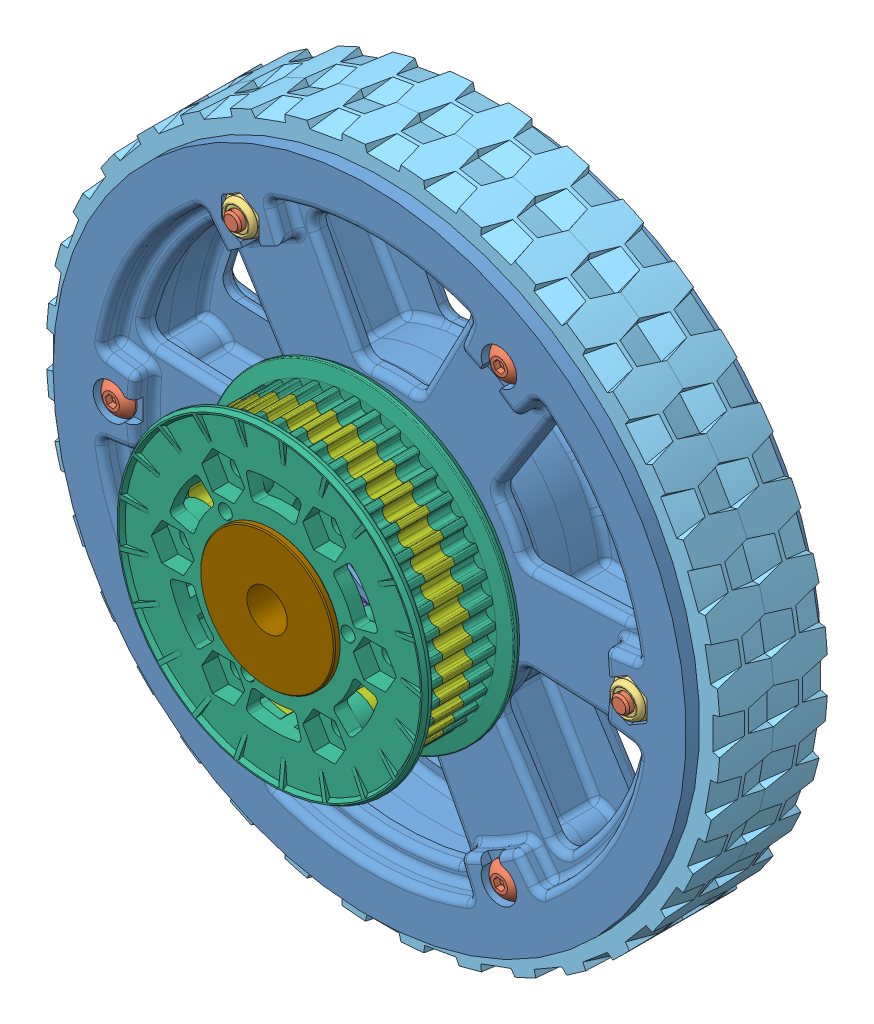
SolidWorks assembly Wheel Drive Free  2.2, configuration 6in Wheel. Lengths in mm.
Overall size (158.75 158.75 58.13).
57 component instances, 11 part files, 21 mates.
Components (placement in the parent):
- 217-2589 1in.20121203-1: 217-2589 1in.20121203 [Default] at origin size (158.75 158.75 36.2)
  - 217-2589-001 Rev3-1: 217-2589-001 Rev3 [Default] at origin size (149.22 149.22 19.81)
  - 217-2589-001 Rev3-2: 217-2589-001 Rev3 [Default] x (-1 0 0) z (0 0 -1) size (149.22 149.22 19.81)
  - SCREW-832-1250-1: SCREW-832-1250 [Default] at (60.96 0 -15.8623) x (0 0 1) z (-1 0 0) size (33.96 7.92 7.92)
  - NUT-832-NYLOCK-1: NUT-832-NYLOCK [Default] at (60.96 0 12.0688) x (0.866025 0.5 0) z (0.5 -0.866025 0) size (10.2 5.86 8.12)
  - BEAM-0750-1: BEAM-0750 [Default] at (11.9062 -20.6222 0.0635) x (0.866025 0.5 0) z (-0.5 0.866025 0) size (7.34 19.93 7.34)
  - BEAM-0750-2: BEAM-0750 [Default] at (-11.9062 -20.6222 0.0635) x (0.866025 -0.5 0) z (0.5 0.866025 0) size (7.34 19.93 7.34)
  - BEAM-0750-3: BEAM-0750 [Default] at (-23.8125 0 0.0635) x (0 -1 0) z (1 0 0) size (7.34 19.93 7.34)
  - BEAM-0750-4: BEAM-0750 [Default] at (-11.9062 20.6222 0.0635) x (-0.866025 -0.5 0) z (0.5 -0.866025 0) size (7.34 19.93 7.34)
  - BEAM-0750-5: BEAM-0750 [Default] at (11.9062 20.6222 0.0635) x (-0.866025 0.5 0) z (-0.5 -0.866025 0) size (7.34 19.93 7.34)
  - BEAM-0750-6: BEAM-0750 [Default] at (23.8125 0 0.0635) x (0 1 0) z (-1 0 0) size (7.34 19.93 7.34)
  - SCREW-832-1250-2: SCREW-832-1250 [Default] at (30.48 52.7929 15.8623) x (0 0 -1) z (0.923728 0.383049 0) size (33.96 7.92 7.92)
  - NUT-832-NYLOCK-2: NUT-832-NYLOCK [Default] at (30.48 52.7929 -12.0688) x (-0.866025 -0.5 0) z (0.5 -0.866025 0) size (10.2 5.86 8.12)
  - NUT-832-NYLOCK-3: NUT-832-NYLOCK [Default] at (30.48 -52.7929 -12.0688) x (0 1 0) z (-1 0 0) size (10.2 5.86 8.12)
  - NUT-832-NYLOCK-4: NUT-832-NYLOCK [Default] at (-60.96 0 -12.0688) x (0.866025 -0.5 0) z (0.5 0.866025 0) size (10.2 5.86 8.12)
  - SCREW-832-1250-3: SCREW-832-1250 [Default] at (-30.48 -52.7929 -15.8623) x (0 0 1) z (0.5 0.866025 0) size (33.96 7.92 7.92)
  - SCREW-832-1250-4: SCREW-832-1250 [Default] at (-30.48 52.7929 -15.8623) x (0 0 1) z (0.5 -0.866025 0) size (33.96 7.92 7.92)
  - NUT-832-NYLOCK-5: NUT-832-NYLOCK [Default] at (-30.48 -52.7929 12.0688) x (0 -1 0) z (-1 0 0) size (10.2 5.86 8.12)
  - NUT-832-NYLOCK-6: NUT-832-NYLOCK [Default] at (-30.48 52.7929 12.0688) x (-0.866025 0.5 0) z (0.5 0.866025 0) size (10.2 5.86 8.12)
  - SCREW-832-1250-5: SCREW-832-1250 [Default] at (30.48 -52.7929 15.8623) x (0 0 -1) z (-0.130134 -0.991496 0) size (33.96 7.92 7.92)
  - SCREW-832-1250-6: SCREW-832-1250 [Default] at (-60.96 0 15.8623) x (0 0 -1) z (-0.793594 0.608447 0) size (33.96 7.92 7.92)
  - 217-2860-001 Rev3-1: 217-2860-001 Rev3 [Default] at (0 0 -6.35) size (158.75 158.75 12.71)
  - 217-2860-001 Rev3-2: 217-2860-001 Rev3 [Default] at (0 0 6.35) size (158.75 158.75 12.71)
- 217-3199-STEP-1: 217-3199-STEP [Default] at (0 0 36.875) x (0 -1 0) z (0 0 1) size (73 73 23.01)
  - 217-3199-001 Rev4-1: 217-3199-001 Rev4 [Default] at origin size (73 73 11.51)
  - 217-3199-001 Rev4-2: 217-3199-001 Rev4 [Default] at (0 0 -17.825) x (-1 0 0) z (0 0 -1) size (73 73 11.51)
  - 217-3199-002 Rev3-1: 217-3199-002 Rev3 [Default] at (0 0 -5.5) x (-1 0 0) z (0 0 1) size (65.74 65.61 14)
- 217-3234-STEP-1: 217-3234-STEP [Default] at (0 0 14.2875) x (0.866025 -0.5 0) z (0.5 0.866025 0)
- 3_8 id 1-1_8 od Flanged Ball Bearing (am-0573)-1: 3_8 id 1-1_8 od Flanged Ball Bearing (am-0573) [Default] at (0 0 36.0749) x (0 0 1) z (-1 0 0)
- 3_8 id 1-1_8 od Flanged Ball Bearing (am-0573)-3: 3_8 id 1-1_8 od Flanged Ball Bearing (am-0573) [Default] at (0 0 -36.0749) x (0 0 -1) z (1 0 0) (suppressed, hidden)
- 217-3234-STEP-2: 217-3234-STEP [Default] at (0 0 -14.2875) x (0.866025 -0.5 0) z (0.5 0.866025 0) (suppressed, hidden)
- 217-3199-STEP-2: 217-3199-STEP [Default] at (0 0 -19.05) x (0 -1 0) z (0 0 1) size (73 73 23.01) (suppressed, hidden)
  - 217-3199-001 Rev4-1: 217-3199-001 Rev4 [Default] at origin size (73 73 11.51)
  - 217-3199-001 Rev4-2: 217-3199-001 Rev4 [Default] at (0 0 -17.825) x (-1 0 0) z (0 0 -1) size (73 73 11.51)
  - 217-3199-002 Rev3-1: 217-3199-002 Rev3 [Default] at (0 0 -5.5) x (-1 0 0) z (0 0 1) size (65.74 65.61 14)
- 3_8 id 1-1_8 od Flanged Ball Bearing (am-0573)-4: 3_8 id 1-1_8 od Flanged Ball Bearing (am-0573) [Default] at (0 0 -8.7249) x (0 0 -1) z (0.923728 0.383049 0)
- 217-2605 1in.20121203-1: 217-2605 1in.20121203 [Default] at origin size (273.24 273.24 34.92) (suppressed, hidden)
  - SBS1_SBS0832-1250SS-1: SBS1_SBS0832-1250SS [Default] at (-86.36 0 -16.4973) x (0 0 1) z (0.950435 -0.310923 0) size (34.41 8.02 7.99)
  - SBS1_SBS0832-1250SS-2: SBS1_SBS0832-1250SS [Default] at (-43.18 74.79 16.4973) x (0 0 -1) z (-0.955409 -0.295284 0) size (34.41 8.02 7.99)
  - NUT-832-NYLOCK-1: NUT-832-NYLOCK [Default] at (-86.36 0 12.0688) x (0.866025 0.5 0) z (0.5 -0.866025 0) size (10.2 5.86 8.12)
  - NUT-832-NYLOCK-2: NUT-832-NYLOCK [Default] at (-43.18 74.79 -12.0688) x (-0.866025 -0.5 0) z (0.5 -0.866025 0) size (10.2 5.86 8.12)
  - 217-2605-001 Rev1-1: 217-2605-001 Rev1 [Default] x (-0.5 0.866025 0) z (0 0 1) size (200.03 200.03 19.71)
  - 217-2605-001 Rev1-2: 217-2605-001 Rev1 [Default] x (-1 0 0) z (0 0 -1) size (200.03 200.03 19.71)
  - NUT-832-NYLOCK-3: NUT-832-NYLOCK [Default] at (86.36 0 -12.0688) x (0 1 0) z (-1 0 0) size (10.2 5.86 8.12)
  - NUT-832-NYLOCK-4: NUT-832-NYLOCK [Default] at (-43.18 -74.79 -12.0688) x (0.866025 -0.5 0) z (0.5 0.866025 0) size (10.2 5.86 8.12)
  - NUT-832-NYLOCK-5: NUT-832-NYLOCK [Default] at (43.18 74.79 12.0688) x (0 -1 0) z (-1 0 0) size (10.2 5.86 8.12)
  - NUT-832-NYLOCK-6: NUT-832-NYLOCK [Default] at (43.18 -74.79 12.0688) x (-0.866025 0.5 0) z (0.5 0.866025 0) size (10.2 5.86 8.12)
  - SBS1_SBS0832-1250SS-3: SBS1_SBS0832-1250SS [Default] at (43.18 74.79 -16.4973) x (0 0 1) z (-0.744485 -0.66764 0) size (34.41 8.02 7.99)
  - SBS1_SBS0832-1250SS-4: SBS1_SBS0832-1250SS [Default] at (43.18 -74.79 -16.4973) x (0 0 1) z (-0.20595 0.978562 0) size (34.41 8.02 7.99)
  - SBS1_SBS0832-1250SS-5: SBS1_SBS0832-1250SS [Default] at (86.36 0 16.4973) x (0 0 -1) z (0.221981 0.975051 0) size (34.41 8.02 7.99)
  - SBS1_SBS0832-1250SS-6: SBS1_SBS0832-1250SS [Default] at (-43.18 -74.79 16.4973) x (0 0 -1) z (0.733429 -0.679767 0) size (34.41 8.02 7.99)
  - BEAM-0750-1: BEAM-0750 [Default] at (-23.8125 0 0) x (0.866025 0.5 0) z (-0.5 0.866025 0) size (7.34 19.93 7.34)
  - BEAM-0750-2: BEAM-0750 [Default] at (-11.9062 20.6222 0) x (0.866025 -0.5 0) z (0.5 0.866025 0) size (7.34 19.93 7.34)
  - BEAM-0750-3: BEAM-0750 [Default] at (11.9062 20.6222 0) x (0 -1 0) z (1 0 0) size (7.34 19.93 7.34)
  - BEAM-0750-4: BEAM-0750 [Default] at (23.8125 0 0) x (-0.866025 -0.5 0) z (0.5 -0.866025 0) size (7.34 19.93 7.34)
  - BEAM-0750-5: BEAM-0750 [Default] at (11.9062 -20.6222 0) x (-0.866025 0.5 0) z (-0.5 -0.866025 0) size (7.34 19.93 7.34)
  - BEAM-0750-6: BEAM-0750 [Default] at (-11.9062 -20.6222 0) x (0 1 0) z (-1 0 0) size (7.34 19.93 7.34)
Mates (geometry in assembly coordinates):
- Coincident1: coincident aligned: plane of 217-2589 1in.20121203-1/217-2589-001 Rev3-2 through (0 0 11.1125) normal (0 0 -1); plane of 217-3234-STEP-1 through (0 0 11.1125) normal (0 0 -1)
- Concentric1: concentric anti-aligned: cylinder of 217-2589 1in.20121203-1/217-2589-001 Rev3-2 through (0 0 11.1125) axis (0 0 -1) radius 14.3; cylinder of 217-3199-STEP-1/217-3199-001 Rev4-2 through (0 0 17.4625) axis (0 0 1) radius 14.3
- Concentric2: concentric: cylinder of 217-2589 1in.20121203-1/BEAM-0750-2 through (-11.9062 -20.6222 9.5885) axis (0 0 -1) radius 2.0955; cylinder of 217-3199-STEP-1/217-3199-002 Rev3-1 through (-11.9062 -20.6222 29.7875) axis (0 0 1) radius 2.1526
- Concentric3: concentric aligned: cylinder of 217-2589 1in.20121203-1/217-2589-001 Rev3-2 through (0 0 11.1125) axis (0 0 -1) radius 14.3; cylinder of 217-3234-STEP-1 through (0 0 17.4625) axis (0 0 -1) radius 14.3
- Concentric4: concentric aligned: cylinder of 217-3234-STEP-1 through (11.9062 20.6222 14.2875) axis (0 0 1) radius 2.1526; cylinder of 217-2589 1in.20121203-1/217-2589-001 Rev3-2 through (11.9062 20.6222 7.9375) axis (0 0 1) radius 2.1526
- Coincident2: coincident anti-aligned: plane of 217-3199-STEP-1/217-3199-001 Rev4-2 through (0 0 17.4625) normal (0 0 -1); plane of 217-3234-STEP-1 through (0 0 17.4625) normal (0 0 1)
- Concentric5: concentric anti-aligned: cylinder of 217-3199-STEP-1/217-3199-001 Rev4-1 through (0 0 38.4625) axis (0 0 -1) radius 14.3; cylinder of 3_8 id 1-1_8 od Flanged Ball Bearing (am-0573)-1 through (0 0 40.0373) axis (0 0 1) radius 14.2875
- Coincident3: coincident anti-aligned: plane of 217-3199-STEP-1/217-3199-001 Rev4-1 through (0 0 38.4625) normal (0 0 1); plane of 3_8 id 1-1_8 od Flanged Ball Bearing (am-0573)-1 through (0 14.2875 38.4625) normal (0 0 -1)
- Concentric6: concentric: cylinder of 217-2589 1in.20121203-1/217-2589-001 Rev3-1 through (0 0 -11.1125) axis (0 0 1) radius 14.3; cylinder of 3_8 id 1-1_8 od Flanged Ball Bearing (am-0573)-4 through (0 0 -12.6873) axis (0 0 -1) radius 14.2875
- Coincident4: coincident aligned: plane of 217-2589 1in.20121203-1/217-2589-001 Rev3-1 through (0 0 -11.1125) normal (0 0 1); plane of 3_8 id 1-1_8 od Flanged Ball Bearing (am-0573)-4 through (-5.4728 13.1978 -11.1125) normal (0 0 1)
- Concentric7: concentric aligned: cylinder of 217-3234-STEP-1 through (0 0 17.4625) axis (0 0 -1) radius 14.3; cylinder of 217-2605 1in.20121203-1/217-2605-001 Rev1-2 through (0 0 11.1125) axis (0 0 -1) radius 14.3
- Concentric8: concentric aligned: cylinder of 217-3234-STEP-1 through (-11.9062 20.6222 14.2875) axis (0 0 1) radius 2.1526; cylinder of 217-2605 1in.20121203-1/217-2605-001 Rev1-2 through (-11.9062 20.6222 7.9375) axis (0 0 1) radius 2.1526
- Coincident5: coincident anti-aligned: plane of 217-3234-STEP-1 through (0 0 11.1125) normal (0 0 -1); plane of 217-2605 1in.20121203-1/217-2605-001 Rev1-2 through (0 0 11.1125) normal (0 0 1)
- Concentric9: concentric anti-aligned: cylinder of 217-3234-STEP-1 through (0 0 17.4625) axis (0 0 -1) radius 14.3; cylinder of 3_8 id 1-1_8 od Flanged Ball Bearing (am-0573)-1 through (0 0 40.0373) axis (0 0 1) radius 4.7625
- Concentric10: concentric anti-aligned: cylinder of 3_8 id 1-1_8 od Flanged Ball Bearing (am-0573)-4 through (0 0 -12.6873) axis (0 0 -1) radius 14.2875; cylinder of 217-2605 1in.20121203-1/217-2605-001 Rev1-1 through (0 0 -11.1125) axis (0 0 1) radius 14.3
- Coincident6: coincident anti-aligned: plane of 3_8 id 1-1_8 od Flanged Ball Bearing (am-0573)-4 through (-5.4728 13.1978 -11.1125) normal (0 0 1); plane of 217-2605 1in.20121203-1/217-2605-001 Rev1-1 through (0 0 -11.1125) normal (0 0 -1)
- Coincident7: coincident aligned: plane of 217-2589 1in.20121203-1/217-2589-001 Rev3-1 through (0 0 0) normal (0 0 1); plane of assembly through (0 0 0) normal (0 0 1)
- Coincident8: coincident aligned: plane of 217-2589 1in.20121203-1/217-2589-001 Rev3-1 through (0 0 0) normal (0 1 0); plane of assembly through (0 0 0) normal (0 1 0)
- Coincident9: coincident aligned: plane of 217-2589 1in.20121203-1/217-2589-001 Rev3-1 through (0 0 0) normal (1 0 0); plane of assembly through (0 0 0) normal (1 0 0)
- Concentric11: concentric anti-aligned: cylinder of 217-2589 1in.20121203-1/217-2589-001 Rev3-1 through (0 0 -11.1125) axis (0 0 1) radius 14.3; cylinder of 3_8 id 1-1_8 od Flanged Ball Bearing (am-0573)-4 through (0 0 -12.6873) axis (0 0 -1) radius 14.2875
- Coincident10: coincident aligned: plane of 217-2589 1in.20121203-1/217-2589-001 Rev3-1 through (0 0 -11.1125) normal (0 0 1); plane of 3_8 id 1-1_8 od Flanged Ball Bearing (am-0573)-4 through (-5.4728 13.1978 -11.1125) normal (0 0 1)
